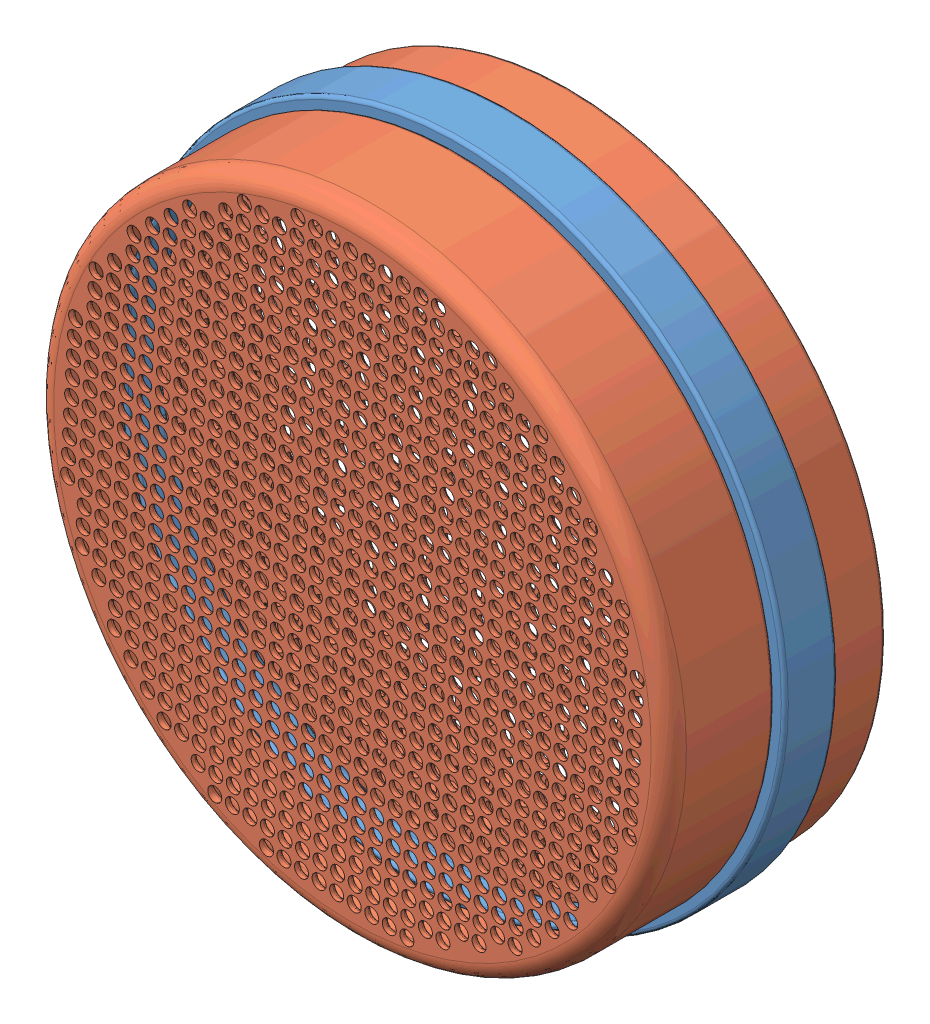
SolidWorks assembly Assemblage1, configuration Défaut. Lengths in mm.
Overall size (237.09 237.09 61.66).
3 component instances, 2 part files, 3 mates.
Components (placement in the parent):
- bague-1: bague [Défaut] at (-12.3097 -4.8273 184) size (186 186 25)
- tamis-4mm-1: tamis-4mm [Défaut] at (-12.3097 -4.8273 197.344) x (0.916012 -0.40115 0) z (0.40115 0.916012 0) size (180 30 180)
- tamis-4mm-2: tamis-4mm [Défaut] at (-12.3097 -4.8273 229) x (0.998426 -0.056076 0) z (0.056076 0.998426 0) size (180 30 180)
Mates (geometry in assembly coordinates):
- Coaxiale1: concentric anti-aligned: cylinder of bague-1 through (-12.3097 -4.8273 199) axis (0 0 -1) radius 91; cylinder of tamis-4mm-1 through (-12.3097 -4.8273 167.344) axis (0 0 1) radius 90
- Coaxiale2: concentric anti-aligned: cylinder of bague-1 through (-12.3097 -4.8273 209) axis (0 0 -1) radius 87; cylinder of tamis-4mm-2 through (-12.3097 -4.8273 199) axis (0 0 1) radius 90
- Tangent2: tangent anti-aligned: plane of bague-1 through (-12.3097 -4.8273 199) normal (0 0 1); torus of tamis-4mm-2
